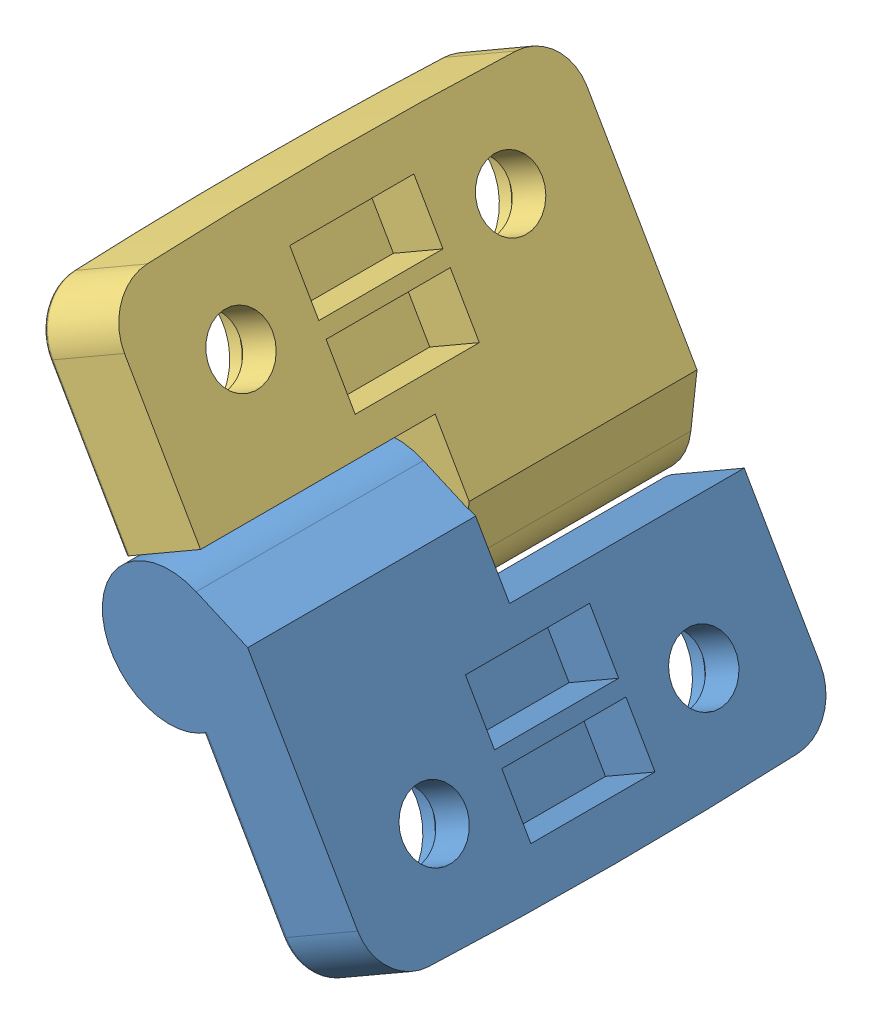
SolidWorks assembly 350.1200A.01, configuration По умолчанию. Lengths in mm.
Overall size (42.37 57.49 48.47).
3 component instances, 3 part files, 4 mates.
Components (placement in the parent):
- 350-1200A-01-2-1: 350-1200A-01-2 [По умолчанию] at (15.951 -8.7675 -23.85) x (0.499988 -0.866032 0) z (0 0 1) size (35.5 15.9 47.7)
- 350-1100A-01-3-1: 350-1100A-01-3 [По умолчанию] at (6.9012 6.9077 -24.3) x (-1 0 0) z (0 1 0) size (12.8 0.8 12.8)
- 350-1200A-01-1-1: 350-1200A-01-1 [По умолчанию] at (-2.1486 22.5829 -23.0823) x (-0.499988 0.866032 0) z (0 0 -1) size (35.5 15.9 47.7)
Mates (geometry in assembly coordinates):
- Совпадение3: coincident anti-aligned: plane of 350-1200A-01-2-1 through (15.951 -8.7675 -23.5) normal (0 0 -1); plane of 350-1100A-01-3-1 through (6.9012 6.9077 -23.5) normal (0 0 1)
- Концентричный1: concentric aligned: circle of 350-1200A-01-2-1; circle of 350-1100A-01-3-1
- Совпадение5: coincident aligned: plane of 350-1200A-01-2-1 through (23.7453 -4.2676 -23.85) normal (0.866032 0.499988 0); plane of 350-1200A-01-1-1 through (-0.8329 38.3104 -23.0823) normal (0.866032 0.499988 0)
- Концентричный2: concentric anti-aligned: circle of 350-1100A-01-3-1; circle of 350-1200A-01-1-1
